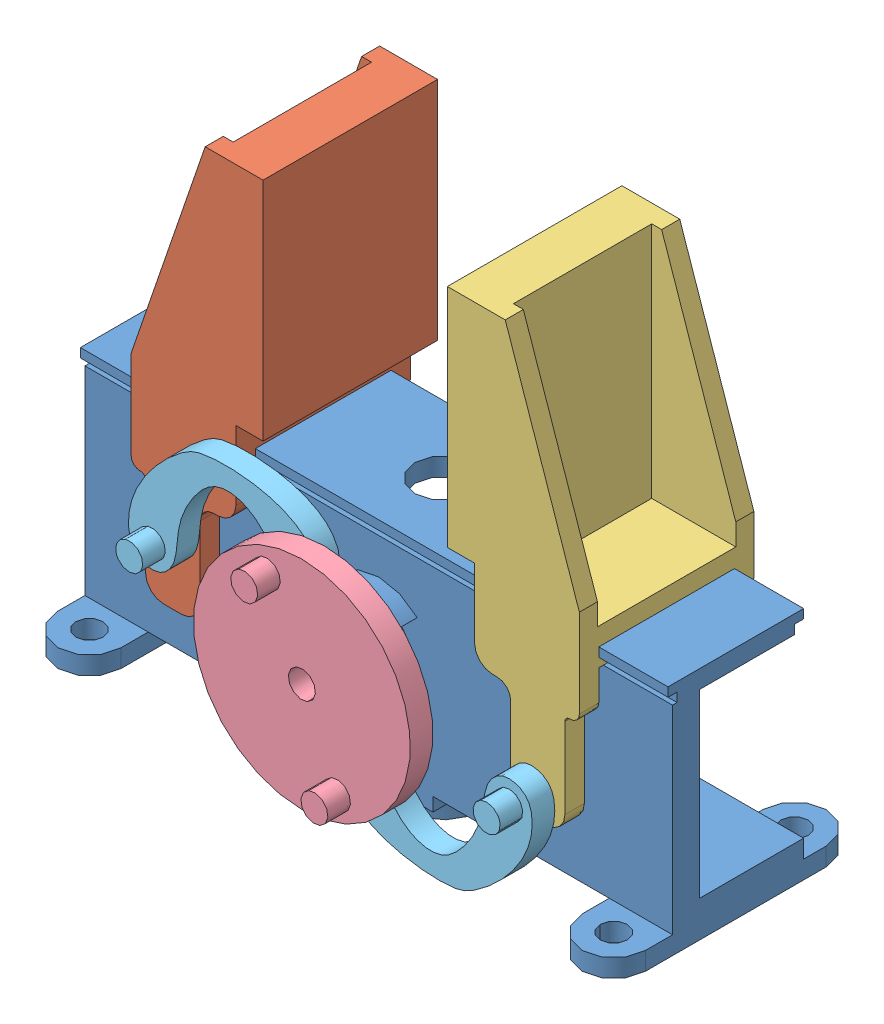
SolidWorks assembly Greep, configuration Default. Lengths in mm.
Overall size (65 57.83 31.5).
6 component instances, 5 part files, 14 mates.
Components (placement in the parent):
- base_central_greep-1: base_central_greep [Default] at origin size (65 28.5 27)
- Late_der_greep-1: Late_der_greep [Default] at (-18.9445 17.2399 -9.65) size (14.6 46.1 21.3)
- Late_izq_greep-2: Late_izq_greep [Default] at (19.0464 17.25 9.65) x (-1 0 0) z (0 0 -1) size (14.6 46.1 21.3)
- acople_servo_greep-1: acople_servo_greep [Default] at (0 0 13) x (-0.408622 0.912704 0) z (0 0 1) size (24 24 10)
- mecanismo_greep-2: mecanismo_greep [Default] at (11.9071 -5.8694 10) x (0.944135 0.329558 0) z (0 0 1) size (22.04 11.02 5)
- mecanismo_greep-3: mecanismo_greep [Default] at (-11.7408 5.4322 10) x (-0.924575 -0.381 0) z (0 0 1) size (22.04 11.02 5)
Mates (geometry in assembly coordinates):
- Coincidente1: coincident anti-aligned: plane of base_central_greep-1 through (-32.5 12 7.5) normal (0 1 0); plane of Late_der_greep-1 through (-12.4445 12 7.5) normal (0 -1 0)
- Coincidente2: coincident anti-aligned: plane of base_central_greep-1 through (-32.5 12 7.5) normal (0 1 0); plane of Late_izq_greep-2 through (12.8464 12 -7.5) normal (0 -1 0)
- Coincidente4: coincident anti-aligned: plane of base_central_greep-1 through (-32.5 12 7.5) normal (0 0 1); plane of Late_der_greep-1 through (-12.4445 12 7.5) normal (0 0 -1)
- Coincidente5: coincident anti-aligned: plane of base_central_greep-1 through (-32.5 12 7.5) normal (0 0 1); plane of Late_izq_greep-2 through (12.8464 12 7.5) normal (0 0 -1)
- Distancia límite1: limit distance = 7.7555 mm aligned: plane of Late_der_greep-1 through (-24.7445 6.6302 9.65) normal (-1 0 0); plane of base_central_greep-1 through (-32.5 0 0) normal (-1 0 0)
- Distancia límite2: limit distance = 7.6536 mm aligned: plane of Late_izq_greep-2 through (24.8464 6.6403 -9.65) normal (1 0 0); plane of base_central_greep-1 through (32.5 0 0) normal (1 0 0)
- Concéntrica4: concentric anti-aligned: cylinder of base_central_greep-1 through (0 0 10) axis (0 0 -1) radius 5.025; cylinder of acople_servo_greep-1 through (0 0 8) axis (0 0 1) radius 5
- Concéntrica5: concentric aligned: cylinder of acople_servo_greep-1 through (3.8819 -8.6707 15) axis (0 0 -1) radius 0.75; cylinder of mecanismo_greep-2 through (3.8819 -8.6707 15) axis (0 0 -1) radius 0.75
- Coincidente7: coincident anti-aligned: plane of acople_servo_greep-1 through (3.8819 -8.6707 15) normal (0 0 -1); plane of mecanismo_greep-2 through (3.8819 -8.6707 15) normal (0 0 1)
- Concéntrica6: concentric aligned: cylinder of acople_servo_greep-1 through (-3.8819 8.6707 15) axis (0 0 -1) radius 0.75; cylinder of mecanismo_greep-3 through (-3.8819 8.6707 15) axis (0 0 -1) radius 0.75
- Coincidente8: coincident anti-aligned: plane of acople_servo_greep-1 through (-3.8819 8.6707 15) normal (0 0 -1); plane of mecanismo_greep-3 through (-3.8819 8.6707 15) normal (0 0 1)
- Concéntrica7: concentric aligned: cylinder of Late_izq_greep-2 through (19.9322 -3.0682 11.65) axis (0 0 -1) radius 0.75; cylinder of mecanismo_greep-2 through (19.9322 -3.0682 12) axis (0 0 -1) radius 0.75
- Concéntrica8: concentric aligned: cylinder of Late_der_greep-1 through (-19.5997 2.1937 11.65) axis (0 0 -1) radius 0.75; cylinder of mecanismo_greep-3 through (-19.5997 2.1937 12) axis (0 0 -1) radius 0.75
- Distancia1: distance = 1 mm anti-aligned: plane of acople_servo_greep-1 through (0 0 8) normal (0 0 -1); plane of base_central_greep-1 through (-33 10 7) normal (0 0 1)
